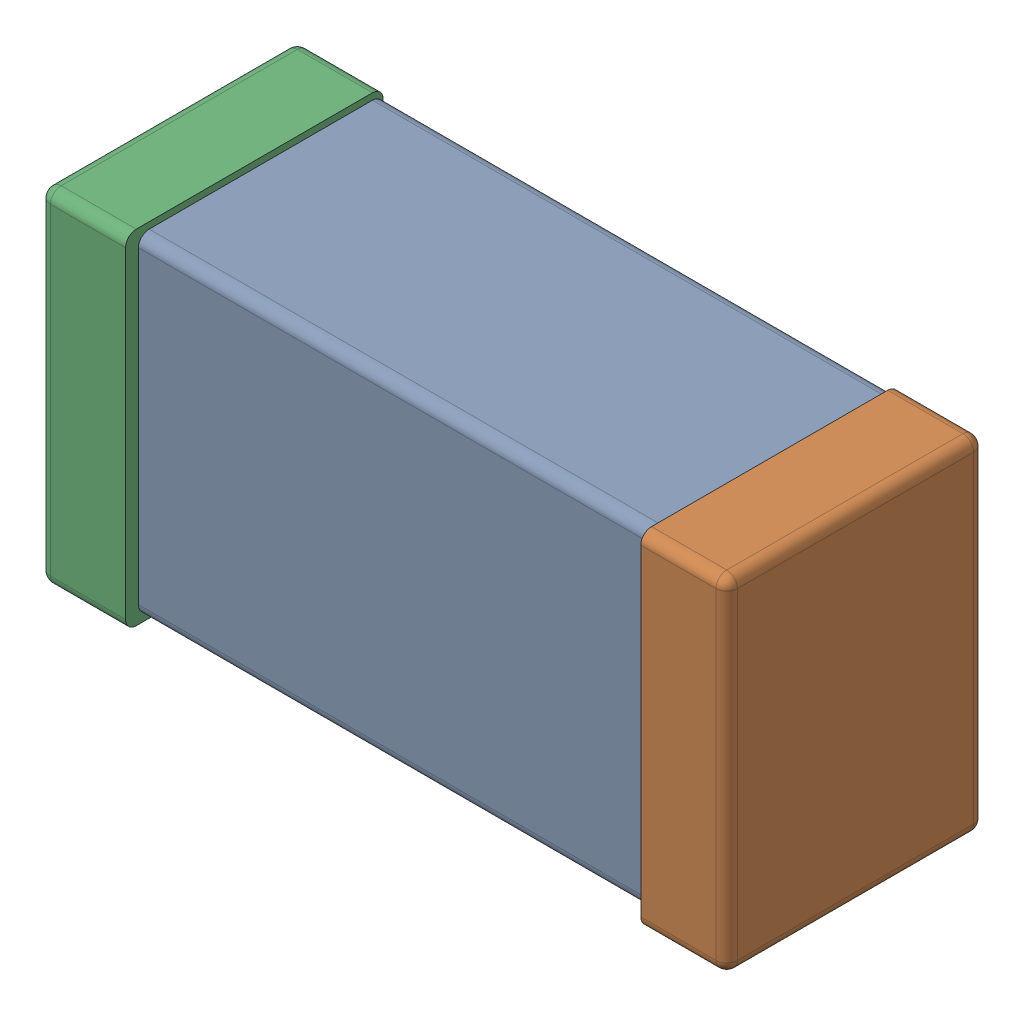
SolidWorks assembly C0603_060, configuration Standard. Lengths in mm.
Overall size (1.6 0.8 0.6).
4 component instances, 3 part files, 0 mates.
Components (placement in the parent):
- C0603_060_1-1: C0603_060_1 [Standard] at (0 0 23.8) size (1.6 0.8 0.6)
  - Part 3_1-1: Part 3_1 [Standard] at (0 0 -23.815) size (1.4 0.77 0.57)
  - Part 2_1-1: Part 2_1 [Standard] at (0 0 -23.8) size (0.2 0.8 0.6)
  - Part 1_1-1: Part 1_1 [Standard] at (0 0 -23.8) size (0.2 0.8 0.6)
